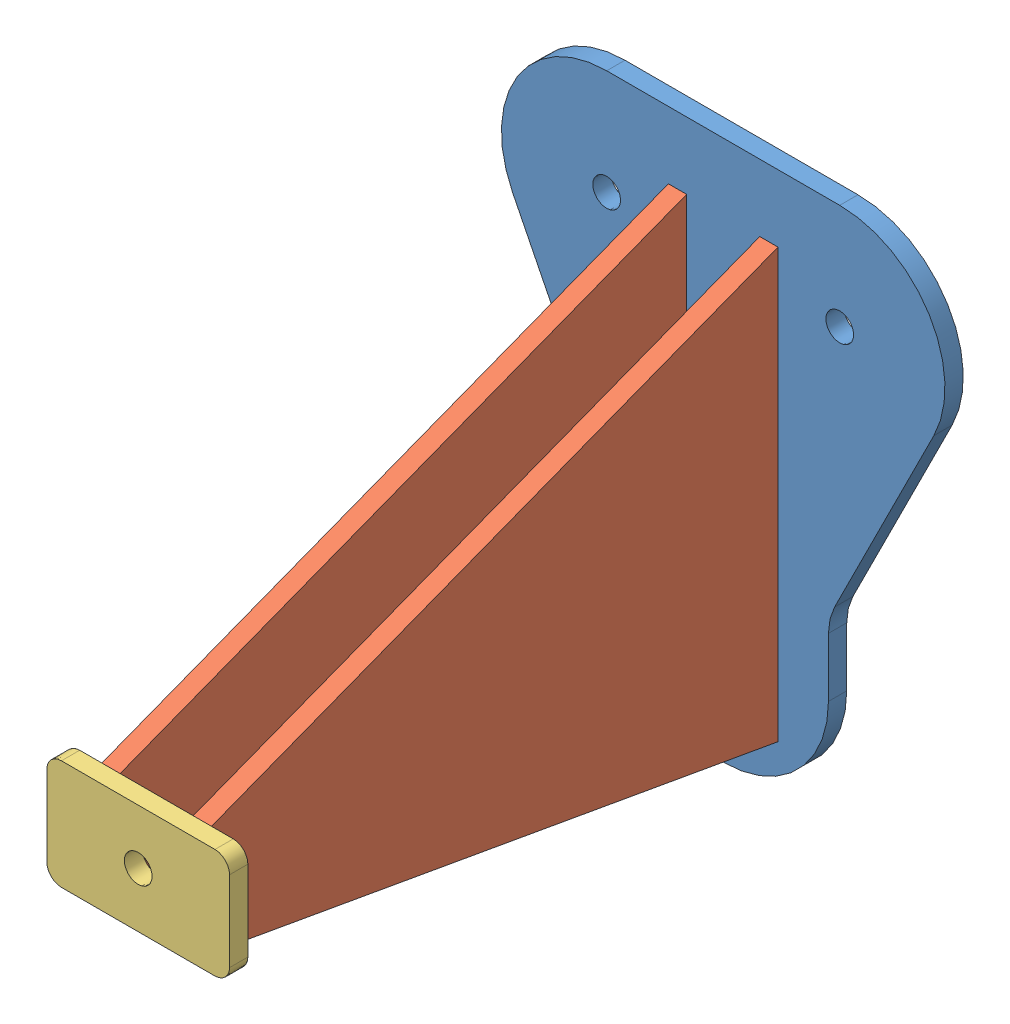
SolidWorks assembly top panel offset mount-steel, configuration Default. Lengths in mm.
Overall size (77.06 93.91 104.77).
4 component instances, 3 part files, 12 mates.
Components (placement in the parent):
- top panel offset base plate-1: top panel offset base plate [Default] at (0.6856 17.5102 0) x (1 0 0) z (0 -1 0) size (77.06 3.17 93.91)
- top panel offset supports-1: top panel offset supports [Default] at (7.0356 17.089 101.6) x (0 0 -1) z (1 0 0) size (104.77 74.41 3.17)
- top panel offset supports-2: top panel offset supports [Default] at (-8.8394 17.089 101.6) x (0 0 -1) z (1 0 0) size (104.77 74.41 3.17)
- top panel offset small plate-1: top panel offset small plate [Default] at (0.6538 17.089 101.6) size (31.75 19.05 3.17)
Mates (geometry in assembly coordinates):
- Coincident4: coincident anti-aligned: plane of top panel offset base plate-1 through (0.6856 17.5102 0) normal (0 0 -1)
- Coincident5: coincident aligned: plane of top panel offset base plate-1 through (0.6856 17.5102 0) normal (0 0 -1); plane of top panel offset supports-1 through (10.2106 17.089 0) normal (0 0 -1)
- Coincident6: coincident anti-aligned: plane of top panel offset base plate-1 through (0.6856 45.4987 -0.001) normal (0 -1 0); plane of top panel offset supports-1 through (10.2106 45.4987 101.6) normal (0 1 0)
- Parallel1: parallel aligned: plane of top panel offset supports-1 through (10.2106 17.089 101.6) normal (1 0 0); plane of top panel offset supports-2 through (-5.6644 17.089 101.6) normal (1 0 0)
- Coincident8: coincident aligned: plane of top panel offset base plate-1 through (0.6856 17.5102 0) normal (0 0 -1); plane of top panel offset supports-2 through (-5.6644 17.089 0) normal (0 0 -1)
- Parallel3: parallel aligned: plane of top panel offset supports-1 through (10.2106 25.3821 104.7963) normal (0 0.933095 0.35963); plane of top panel offset supports-2 through (-5.6644 25.3821 104.7963) normal (0 0.933095 0.35963)
- Coincident10: coincident anti-aligned: plane of top panel offset base plate-1 through (0.6856 13.7487 -0.001) normal (0 1 0); plane of top panel offset supports-2 through (-5.6644 13.7487 101.6) normal (0 -1 0)
- Coincident11: coincident anti-aligned: plane of top panel offset base plate-1 through (-8.8394 17.5102 -0.001) normal (1 0 0); plane of top panel offset supports-2 through (-8.8394 17.089 101.6) normal (-1 0 0)
- Coincident13: coincident anti-aligned: plane of top panel offset supports-1 through (10.2106 17.089 101.6) normal (0 0 1); plane of top panel offset small plate-1 through (0.6538 17.089 101.6) normal (0 0 -1)
- Parallel4: parallel aligned: plane of top panel offset base plate-1 through (0.6856 76.1945 3.175) normal (0 1 0); plane of top panel offset small plate-1 through (0.6538 26.614 104.775) normal (0 1 0)
- Coincident17: coincident: line of top panel offset supports-2 through (-5.6644 7.564 101.6) axis (-1 0 0); plane of top panel offset small plate-1 through (0.6538 7.564 104.775) normal (0 -1 0)
- Coincident18: coincident anti-aligned: plane of top panel offset base plate-1 through (10.2106 17.5102 -0.001) normal (-1 0 0); plane of top panel offset supports-1 through (10.2106 17.089 101.6) normal (1 0 0)
